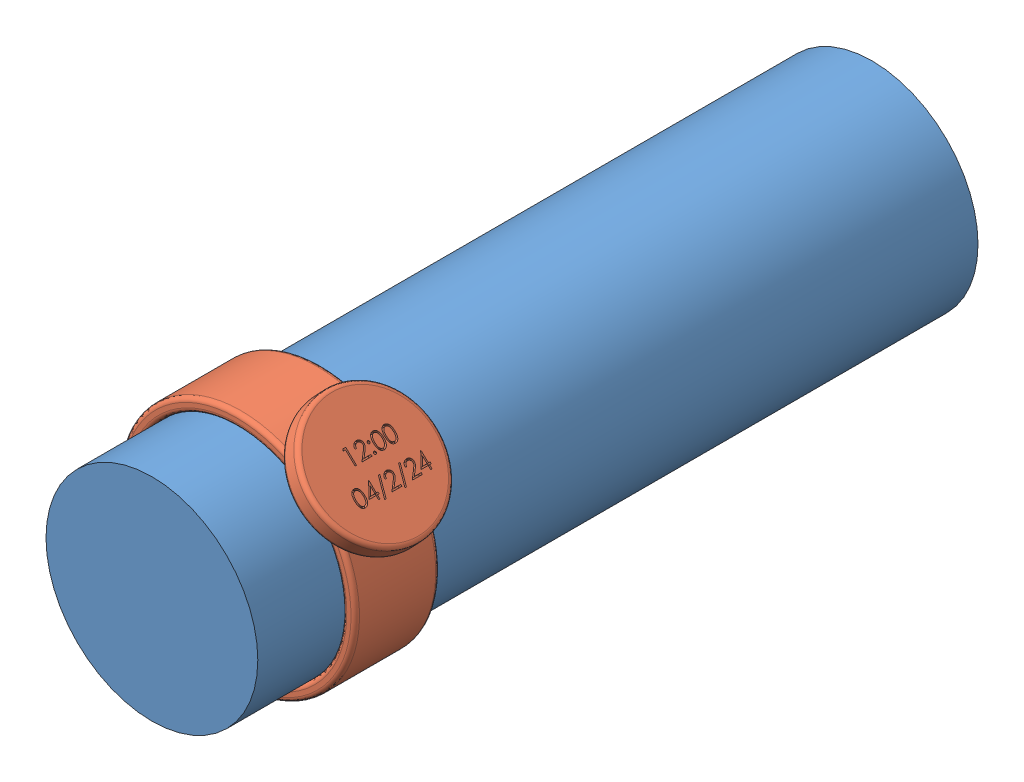
SolidWorks assembly Arm&watch, configuration Default. Lengths in mm.
Overall size (82.61 82.8 170).
2 component instances, 2 part files, 6 mates.
Components (placement in the parent):
- arm-1: arm [Default] at origin size (50 50 170)
- watch-1: watch [Default] at (0 0 130) x (0.68851 0.725226 0) z (0 0 1) size (61 56 30)
Mates (geometry in assembly coordinates):
- Coincident1: coincident aligned: plane of arm-1 through (0 0 0) normal (0 0 1)
- Coincident2: coincident aligned: plane of arm-1 through (0 0 0) normal (0 1 0)
- Coincident3: coincident aligned: plane of arm-1 through (0 0 0) normal (1 0 0)
- Coincident4: coordinate: point of arm-1
- Concentric1: concentric aligned: cylinder of arm-1 through (0 0 170) axis (0 0 -1) radius 25; cylinder of watch-1 through (0 0 150) axis (0 0 -1) radius 25
- Distance1: distance = 20 mm aligned: plane of watch-1 through (0 0 150) normal (0 0 1); plane of arm-1 through (0 0 170) normal (0 0 1)
